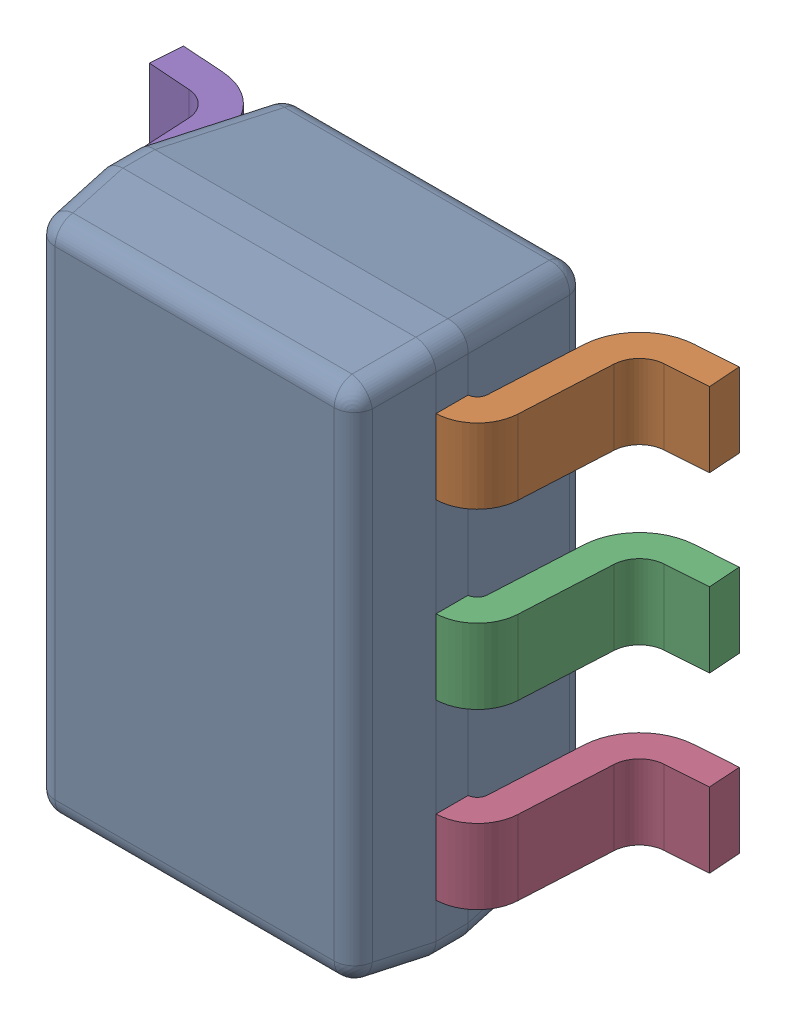
SolidWorks assembly U16, configuration ﾃﾞﾌｫﾙﾄ. Lengths in mm.
Overall size (2.1 2 1.01).
7 component instances, 2 part files, 0 mates.
Components (placement in the parent):
- DCK0005A-1: DCK0005A [ﾃﾞﾌｫﾙﾄ] at (77 17.25 0) x (-1 0 0) z (0 0 1) size (2.1 2 1.01)
  - BODY-SOT_2-1: BODY-SOT_2 [ﾃﾞﾌｫﾙﾄ] at (0 0 0.72) x (0 -1 0) z (-1 0 0) size (2 0.92 1.25)
  - LEAD-SOT_2-1: LEAD-SOT_2 [ﾃﾞﾌｫﾙﾄ] at (-0.6816 -0.65 0.15) x (0 -1 0) z (-1 0 0) size (0.28 0.72 0.43)
  - LEAD-SOT_2-2: LEAD-SOT_2 [ﾃﾞﾌｫﾙﾄ] at (-0.6816 0 0.15) x (0 -1 0) z (-1 0 0) size (0.28 0.72 0.43)
  - LEAD-SOT_2-3: LEAD-SOT_2 [ﾃﾞﾌｫﾙﾄ] at (-0.6816 0.65 0.15) x (0 -1 0) z (-1 0 0) size (0.28 0.72 0.43)
  - LEAD-SOT_2-4: LEAD-SOT_2 [ﾃﾞﾌｫﾙﾄ] at (0.6816 -0.65 0.15) x (0 1 0) z (1 0 0) size (0.28 0.72 0.43)
  - LEAD-SOT_2-5: LEAD-SOT_2 [ﾃﾞﾌｫﾙﾄ] at (0.6816 0.65 0.15) x (0 1 0) z (1 0 0) size (0.28 0.72 0.43)
